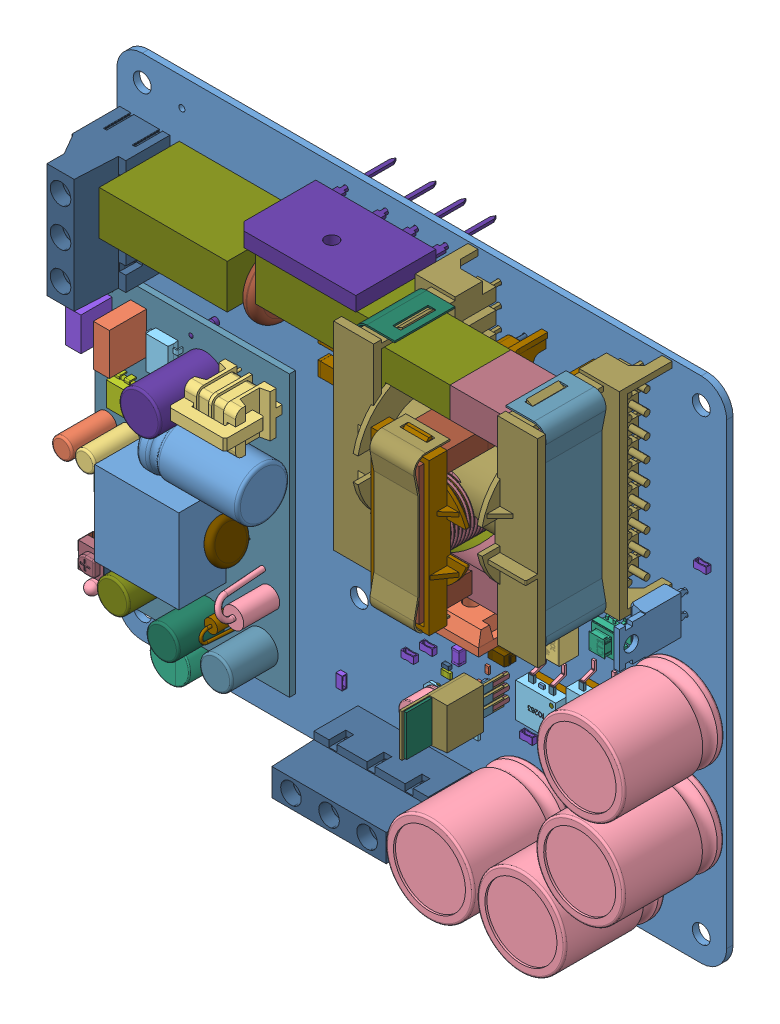
SolidWorks assembly VFD, configuration Default. Lengths in mm.
Overall size (152.4 127.13 60.49).
435 component instances, 101 part files, 0 mates.
Components (placement in the parent):
- Board-1: Board [Default] at origin size (152.4 127.13 1.59)
- R32-1: R32 [Default] at origin size (1.75 0.95 0.55)
  - RES_0603_(1608_metric)-1: RES_0603_(1608_metric) [Default] at (62.5869 45.7709 -0.013) size (1.75 0.95 0.55)
- C29-1: C29 [Default] at origin size (6.6 7 7.01)
  - User_Library-CAPSMD6_3x7-1: User_Library-CAPSMD6_3x7 [Default] at (80.5194 27.0821 0) x (1 0 0) z (0 0 1) size (6.6 7 7.01)
    - User_Library-CAPSMD6_3x3_9_CAP003-1: User_Library-CAPSMD6_3x3_9_CAP003 [Default] at origin size (0.65 2.6 0.32)
    - User_Library-CAPSMD6_3x3_9_CAP-1: User_Library-CAPSMD6_3x3_9_CAP [Default] at origin size (6.3 6.3 6.37)
    - User_Library-CAPSMD6_3x3_9_CAP001-1: User_Library-CAPSMD6_3x3_9_CAP001 [Default] at origin size (6.6 6.6 0.64)
    - User_Library-CAPSMD6_3x3_9_CAP002-1: User_Library-CAPSMD6_3x3_9_CAP002 [Default] at origin size (5.11 1.47 0.01)
    - User_Library-CAPSMD6_3x3_9_CAP004-1: User_Library-CAPSMD6_3x3_9_CAP004 [Default] at origin size (0.65 2.6 0.32)
- C28-1: C28 [Default] at origin size (6.6 7 7.01)
  - User_Library-CAPSMD6_3x7-1: User_Library-CAPSMD6_3x7 [Default] at (87.6314 26.9551 0) size (6.6 7 7.01)
    - User_Library-CAPSMD6_3x3_9_CAP003-1: User_Library-CAPSMD6_3x3_9_CAP003 [Default] at origin size (0.65 2.6 0.32)
    - User_Library-CAPSMD6_3x3_9_CAP-1: User_Library-CAPSMD6_3x3_9_CAP [Default] at origin size (6.3 6.3 6.37)
    - User_Library-CAPSMD6_3x3_9_CAP001-1: User_Library-CAPSMD6_3x3_9_CAP001 [Default] at origin size (6.6 6.6 0.64)
    - User_Library-CAPSMD6_3x3_9_CAP002-1: User_Library-CAPSMD6_3x3_9_CAP002 [Default] at origin size (5.11 1.47 0.01)
    - User_Library-CAPSMD6_3x3_9_CAP004-1: User_Library-CAPSMD6_3x3_9_CAP004 [Default] at origin size (0.65 2.6 0.32)
- TP17-1: TP17 [Default] at origin size (1.6 3.2 1.25)
  - c-1625854-1-ba-3d-1: c-1625854-1-ba-3d [Default] at (64.0474 73.9139 0.635) x (0 1 0) z (1 0 0) size (3.2 1.25 1.6)
- TP16-1: TP16 [Default] at origin size (3.2 1.6 1.25)
  - c-1625854-1-ba-3d-1: c-1625854-1-ba-3d [Default] at (73.7884 31.5341 0.635) x (-1 0 0) z (0 1 0) size (3.2 1.25 1.6)
- TP15-1: TP15 [Default] at origin size (3.2 1.6 1.25)
  - c-1625854-1-ba-3d-1: c-1625854-1-ba-3d [Default] at (103.5063 28.8671 0.635) x (-1 0 0) z (0 1 0) size (3.2 1.25 1.6)
- TP14-1: TP14 [Default] at origin size (3.2 1.6 1.25)
  - c-1625854-1-ba-3d-1: c-1625854-1-ba-3d [Default] at (97.9183 48.5521 0.635) x (-1 0 0) z (0 1 0) size (3.2 1.25 1.6)
- TP13-1: TP13 [Default] at origin size (1.6 3.2 1.25)
  - c-1625854-1-ba-3d-1: c-1625854-1-ba-3d [Default] at (67.7812 74.8031 0.635) x (0 -1 0) z (-1 0 0) size (3.2 1.25 1.6)
- TP12-1: TP12 [Default] at origin size (3.2 1.6 1.25)
  - c-1625854-1-ba-3d-1: c-1625854-1-ba-3d [Default] at (81.6116 71.7677 0.635) x (-1 0 0) z (0 1 0) size (3.2 1.25 1.6)
- TP11-1: TP11 [Default] at origin size (1.6 3.2 1.25)
  - c-1625854-1-ba-3d-1: c-1625854-1-ba-3d [Default] at (72.9374 79.3749 0.635) x (0 1 0) z (1 0 0) size (3.2 1.25 1.6)
- TP10-1: TP10 [Default] at origin size (3.2 1.6 1.25)
  - c-1625854-1-ba-3d-1: c-1625854-1-ba-3d [Default] at (72.5184 42.9641 0.635) x (-1 0 0) z (0 1 0) size (3.2 1.25 1.6)
- TP9-1: TP9 [Default] at origin size (1.6 3.2 1.25)
  - c-1625854-1-ba-3d-1: c-1625854-1-ba-3d [Default] at (57.5704 16.8909 0.635) x (0 1 0) z (1 0 0) size (3.2 1.25 1.6)
- TP8-1: TP8 [Default] at origin size (3.2 1.6 1.25)
  - c-1625854-1-ba-3d-1: c-1625854-1-ba-3d [Default] at (120.0417 71.0565 0.635) x (-1 0 0) z (0 1 0) size (3.2 1.25 1.6)
- TP7-1: TP7 [Default] at origin size (3.2 1.6 1.25)
  - c-1625854-1-ba-3d-1: c-1625854-1-ba-3d [Default] at (78.4873 35.5981 0.635) x (-1 0 0) z (0 1 0) size (3.2 1.25 1.6)
- TP6-1: TP6 [Default] at origin size (3.2 1.6 1.25)
  - c-1625854-1-ba-3d-1: c-1625854-1-ba-3d [Default] at (97.9183 53.7591 0.635) x (-1 0 0) z (0 1 0) size (3.2 1.25 1.6)
- TP5-1: TP5 [Default] at origin size (1.6 3.2 1.25)
  - c-1625854-1-ba-3d-1: c-1625854-1-ba-3d [Default] at (93.6774 68.9609 0.635) x (0 1 0) z (1 0 0) size (3.2 1.25 1.6)
- TP4-1: TP4 [Default] at origin size (3.2 1.6 1.25)
  - c-1625854-1-ba-3d-1: c-1625854-1-ba-3d [Default] at (146.9149 87.5411 0.635) x (-1 0 0) z (0 1 0) size (3.2 1.25 1.6)
- TP3-1: TP3 [Default] at origin size (3.2 1.6 1.25)
  - c-1625854-1-ba-3d-1: c-1625854-1-ba-3d [Default] at (135.5102 72.6059 0.635) x (1 0 0) z (0 -1 0) size (3.2 1.25 1.6)
- TP2-1: TP2 [Default] at origin size (1.6 3.2 1.25)
  - c-1625854-1-ba-3d-1: c-1625854-1-ba-3d [Default] at (80.9384 85.5979 0.635) x (0 1 0) z (1 0 0) size (3.2 1.25 1.6)
- D11-1: D11 [Default] at origin size (1.35 2.6 1.1)
  - SOD323-1: SOD323 [Default] at (65.7872 47.0101 0) x (0 -1 0) z (0 0 1) size (2.6 1.35 1.1)
- P2-1: P2 [Default] at origin size (29.16 12.5 26.5)
  - c-796739-3-b-3d-1: c-796739-3-b-3d [Default] at (74.682 0.5047 7) x (1 0 0) z (0 -1 0) size (29.16 26.5 12.5)
- P1-1: P1 [Default] at origin size (12.5 29.16 26.5)
  - c-796739-3-b-3d-1: c-796739-3-b-3d [Default] at (0.887 98.6742 7) x (0 -1 0) z (-1 0 0) size (29.16 26.5 12.5)
- VR1-1: VR1 [Default] at origin size (4.2 15.5 21.5)
  - User_Library-S14K25_MOV-1: User_Library-S14K25_MOV [Default] at (51.4159 105.2829 0.5) x (0 -1 0) z (-1 0 0) size (15.5 21.5 4.2)
- L2-1: L2 [Default] at origin size (51 49.6 42.6)
  - User_Library-ETD44_NO_AIRGAP-1: User_Library-ETD44_NO_AIRGAP [Default] at (113.2599 101.8636 0) x (0 1 0) z (0 0 1) size (49.6 51 42.6)
    - User_Library-ETD44_NO_AIRGAP_CoilFormerETD44-1: User_Library-ETD44_NO_AIRGAP_CoilFormerETD44 [Default] at origin size (49.6 51 42.6)
    - User_Library-ETD44_NO_AIRGAP_ETD44_core1-1: User_Library-ETD44_NO_AIRGAP_ETD44_core1 [Default] at origin size (43.8 22.5 15.2)
    - User_Library-ETD44_NO_AIRGAP_ClipETD44_2-1: User_Library-ETD44_NO_AIRGAP_ClipETD44_2 [Default] at origin size (48.8 10 15)
    - User_Library-ETD44_NO_AIRGAP_ClipETD44_1-1: User_Library-ETD44_NO_AIRGAP_ClipETD44_1 [Default] at origin size (48.8 10 15)
    - User_Library-ETD44_NO_AIRGAP_ETD44_core2-1: User_Library-ETD44_NO_AIRGAP_ETD44_core2 [Default] at origin size (43.8 22.5 15.2)
- D5-1: D5 [Default] at origin size (4.7 2.71 1.1)
  - 1281330688-1: 1281330688 [Default] at (102.8713 61.722 0) x (1 0 0) z (0 0 1) size (4.7 2.71 1.1)
    - Body-1: Body [Default] at (-2 -1.35 0) size (4.01 2.71 1.1)
      - Open_CASCADE_STEP_translator_6.8_1.1.1-1: Open_CASCADE_STEP_translator_6.8_1.1.1 [Default] at origin size (4.01 2.71 1.1)
    - lead-1: lead [Default] at (-2.35 -0.875 0) size (0.72 1.75 0.2)
    - lead-2: lead [Default] at (2.35 0.875 0) x (-1 0 0) z (0 0 1) size (0.72 1.75 0.2)
- D2-1: D2 [Default] at origin size (4.5 9.65 28.38)
  - User_Library-TO_220-2-1: User_Library-TO_220-2 [Default] at (144.3394 76.1879 4.445) x (0 -1 0) z (0 0 -1) size (9.65 4.5 28.38)
- Q1-1: Q1 [Default] at origin size (15.9 5.1 41.13)
  - User_Library-PG-TO247-3-21-1: User_Library-PG-TO247-3-21 [Default] at (115.7489 63.7671 4.3942) x (-1 0 0) z (0 1 0) size (15.9 41.13 5.1)
- U1-1: U1 [Default] at origin size (13.01 10.3 2.66)
  - 809572592-1: 809572592 [Default] at (83.9483 50.292 0) x (0 1 0) z (0 0 1) size (10.3 13.01 2.66)
    - Open_CASCADE_STEP_translator_6.8_1.1-1: Open_CASCADE_STEP_translator_6.8_1.1 [Default] at (-3.8 -6.5 0.001) size (0.95 0.95 0)
    - Body_2-1: Body_2 [Default] at (-3.8 -6.5 0) size (7.61 13.01 2.56)
      - Open_CASCADE_STEP_translator_6.8_1.2.1-1: Open_CASCADE_STEP_translator_6.8_1.2.1 [Default] at origin size (7.61 13.01 2.56)
    - Leader-1: Leader [Default] at (-3.8 -5.715 0) x (-1 0 0) z (0 0 1) size (1.35 0.41 1.43)
    - Leader-2: Leader [Default] at (-3.8 -4.445 0) x (-1 0 0) z (0 0 1) size (1.35 0.41 1.43)
    - Leader-3: Leader [Default] at (-3.8 -3.175 0) x (-1 0 0) z (0 0 1) size (1.35 0.41 1.43)
    - Leader-4: Leader [Default] at (-3.8 -1.905 0) x (-1 0 0) z (0 0 1) size (1.35 0.41 1.43)
    - Leader-5: Leader [Default] at (-3.8 -0.635 0) x (-1 0 0) z (0 0 1) size (1.35 0.41 1.43)
    - Leader-6: Leader [Default] at (-3.8 0.635 0) x (-1 0 0) z (0 0 1) size (1.35 0.41 1.43)
    - Leader-7: Leader [Default] at (-3.8 1.905 0) x (-1 0 0) z (0 0 1) size (1.35 0.41 1.43)
    - Leader-8: Leader [Default] at (-3.8 3.175 0) x (-1 0 0) z (0 0 1) size (1.35 0.41 1.43)
    - Leader-9: Leader [Default] at (-3.8 4.445 0) x (-1 0 0) z (0 0 1) size (1.35 0.41 1.43)
    - Leader-10: Leader [Default] at (-3.8 5.715 0) x (-1 0 0) z (0 0 1) size (1.35 0.41 1.43)
    - Leader-11: Leader [Default] at (3.8 -5.715 0) size (1.35 0.41 1.43)
    - Leader-12: Leader [Default] at (3.8 -4.445 0) size (1.35 0.41 1.43)
    - Leader-13: Leader [Default] at (3.8 -3.175 0) size (1.35 0.41 1.43)
    - Leader-14: Leader [Default] at (3.8 -1.905 0) size (1.35 0.41 1.43)
    - Leader-15: Leader [Default] at (3.8 -0.635 0) size (1.35 0.41 1.43)
    - Leader-16: Leader [Default] at (3.8 0.635 0) size (1.35 0.41 1.43)
    - Leader-17: Leader [Default] at (3.8 1.905 0) size (1.35 0.41 1.43)
    - Leader-18: Leader [Default] at (3.8 3.175 0) size (1.35 0.41 1.43)
    - Leader-19: Leader [Default] at (3.8 4.445 0) size (1.35 0.41 1.43)
    - Leader-20: Leader [Default] at (3.8 5.715 0) size (1.35 0.41 1.43)
- TR1-1: TR1 [Default] at origin size (7.6 8.13 5.36)
  - Coilcraft-CST1-1: Coilcraft-CST1 [Default] at (125.2232 61.0871 0.1) x (0 1 0) z (1 0 0) size (8.13 5.36 7.6)
- R20-1: R20 [Default] at origin size (0.95 1.75 0.55)
  - RES_0603_(1608_metric)-1: RES_0603_(1608_metric) [Default] at (79.1224 40.132 -0.013) x (0 -1 0) z (0 0 1) size (1.75 0.95 0.55)
- R16-1: R16 [Default] at origin size (1.75 0.95 0.55)
  - RES_0603_(1608_metric)-1: RES_0603_(1608_metric) [Default] at (71.6292 54.6099 -0.013) x (-1 0 0) z (0 0 1) size (1.75 0.95 0.55)
- R13-1: R13 [Default] at origin size (0.95 1.75 0.55)
  - RES_0603_(1608_metric)-1: RES_0603_(1608_metric) [Default] at (68.5814 91.059 -0.013) x (0 -1 0) z (0 0 1) size (1.75 0.95 0.55)
- R10-1: R10 [Default] at origin size (2.2 1.35 0.7)
  - RES_0805_(2012_metric)-1: RES_0805_(2012_metric) [Default] at (71.1214 103.1241 -0.013) x (1 0 0) z (0 0 1) size (2.2 1.35 0.7)
- R9-1: R9 [Default] at origin size (2.2 1.35 0.7)
  - RES_0805_(2012_metric)-1: RES_0805_(2012_metric) [Default] at (67.5494 97.9171 -0.013) x (1 0 0) z (0 0 1) size (2.2 1.35 0.7)
- R6-1: R6 [Default] at origin size (2.2 1.35 0.7)
  - RES_0805_(2012_metric)-1: RES_0805_(2012_metric) [Default] at (66.5494 103.1241 -0.013) x (1 0 0) z (0 0 1) size (2.2 1.35 0.7)
- R5-1: R5 [Default] at origin size (2.2 1.35 0.7)
  - RES_0805_(2012_metric)-1: RES_0805_(2012_metric) [Default] at (63.5014 97.9171 -0.013) x (1 0 0) z (0 0 1) size (2.2 1.35 0.7)
- R4-1: R4 [Default] at origin size (0.95 1.75 0.55)
  - RES_0603_(1608_metric)-1: RES_0603_(1608_metric) [Default] at (95.8862 58 -0.013) x (0 1 0) z (0 0 1) size (1.75 0.95 0.55)
- C17-1: C17 [Default] at origin size (1.8 3.4 1.8)
  - CAPC3216X180N_-_1206_(3216_metric)-1: CAPC3216X180N_-_1206_(3216_metric) [Default] at (78.9952 61.7221 0) x (0 1 0) z (0 0 1) size (3.4 1.8 1.8)
- C18-1: C18 [Default] at origin size (1.8 3.4 1.8)
  - CAPC3216X180N_-_1206_(3216_metric)-1: CAPC3216X180N_-_1206_(3216_metric) [Default] at (86.3614 37.3379 0) x (0 -1 0) z (0 0 1) size (3.4 1.8 1.8)
- C16-1: C16 [Default] at origin size (4.9 3.6 2.8)
  - CAP_1812-1: CAP_1812 [Default] at (66.5492 87.2489 -0.013) x (-1 0 0) z (0 0 1) size (4.9 3.6 2.8)
- C15-1: C15 [Default] at origin size (0.9 1.7 0.9)
  - CAP_0603-1: CAP_0603 [Default] at (85.8533 60.706 -0.013) x (0 -1 0) z (0 0 1) size (1.7 0.9 0.9)
- C13-1: C13 [Default] at origin size (4.9 3.6 2.8)
  - CAP_1812-1: CAP_1812 [Default] at (66.5492 94.7419 -0.013) x (-1 0 0) z (0 0 1) size (4.9 3.6 2.8)
- C10-1: C10 [Default] at origin size (0.9 1.7 0.9)
  - CAP_0603-1: CAP_0603 [Default] at (94.1083 58.039 -0.013) x (0 -1 0) z (0 0 1) size (1.7 0.9 0.9)
- C7-1: C7 [Default] at origin size (0.9 1.7 0.9)
  - CAP_0603-1: CAP_0603 [Default] at (80.7732 40.132 -0.013) x (0 1 0) z (0 0 1) size (1.7 0.9 0.9)
- C8-1: C8 [Default] at origin size (0.9 1.7 0.9)
  - CAP_0603-1: CAP_0603 [Default] at (99.0614 72.898 -0.013) x (0 -1 0) z (0 0 1) size (1.7 0.9 0.9)
- C9-1: C9 [Default] at origin size (0.9 1.7 0.9)
  - CAP_0603-1: CAP_0603 [Default] at (101.0934 72.898 -0.013) x (0 -1 0) z (0 0 1) size (1.7 0.9 0.9)
- C11-1: C11 [Default] at origin size (3.4 1.8 1.8)
  - CAPC3216X180N_-_1206_(3216_metric)-1: CAPC3216X180N_-_1206_(3216_metric) [Default] at (128.7792 69.7229 0) x (-1 0 0) z (0 0 1) size (3.4 1.8 1.8)
- C12-1: C12 [Default] at origin size (1.7 0.9 0.9)
  - CAP_0603-1: CAP_0603 [Default] at (75.0583 51.6891 -0.013) x (1 0 0) z (0 0 1) size (1.7 0.9 0.9)
- C14-1: C14 [Default] at origin size (1.7 0.9 0.9)
  - CAP_0603-1: CAP_0603 [Default] at (71.7563 49.9111 -0.013) x (1 0 0) z (0 0 1) size (1.7 0.9 0.9)
- C19-1: C19 [Default] at origin size (0.9 1.7 0.9)
  - CAP_0603-1: CAP_0603 [Default] at (73.9152 61.468 -0.013) x (0 1 0) z (0 0 1) size (1.7 0.9 0.9)
- C24-1: C24 [Default] at origin size (0.9 1.7 0.9)
  - CAP_0603-1: CAP_0603 [Default] at (84.2022 60.706 -0.013) x (0 1 0) z (0 0 1) size (1.7 0.9 0.9)
- C25-1: C25 [Default] at origin size (1.7 0.9 0.9)
  - CAP_0603-1: CAP_0603 [Default] at (82.9322 33.0199 -0.013) x (-1 0 0) z (0 0 1) size (1.7 0.9 0.9)
- D4-1: D4 [Default] at origin size (3.6 1.96 1.08)
  - 809534704-1: 809534704 [Default] at (117.5503 75.311 0) x (1 0 0) z (0 0 1) size (3.6 1.96 1.08)
    - Body_3-1: Body_3 [Default] at (-1.5 -0.975 0) size (3.01 1.96 1.08)
      - Open_CASCADE_STEP_translator_6.8_1.1.1_2-1: Open_CASCADE_STEP_translator_6.8_1.1.1_2 [Default] at origin size (3.01 1.96 1.08)
    - lead_2-1: lead_2 [Default] at (-1.8 -0.4125 0) size (0.68 0.82 0.2)
    - lead_2-2: lead_2 [Default] at (1.8 0.4125 0) x (-1 0 0) z (0 0 1) size (0.68 0.82 0.2)
- D8-1: D8 [Default] at origin size (10 15.67 4.89)
  - SW3dPS-TO263-3S-1: SW3dPS-TO263-3S [Default] at (122.0482 47.6011 1.6271) x (-1 0 0) z (0 0 1) size (10 15.67 4.89)
    - SW3dPS-TO263-3S_Board9-1: SW3dPS-TO263-3S_Board9 [Default] at (0 0 -0.0938) size (0.01 0.01 0.11)
    - SW3dPS-TO263-3S_Free-Models5-1: SW3dPS-TO263-3S_Free-Models5 [Default] at origin size (10 15.67 4.89)
      - SW3dPS-TO263-3S_450155985-1: SW3dPS-TO263-3S_450155985 [Default] at (2.54 -0.83 1.2127) size (1.2 1.68 0.6)
        - SW3dPS-TO263-3S_Extruded14-1: SW3dPS-TO263-3S_Extruded14 [Default] at origin size (1.2 1.68 0.6)
      - SW3dPS-TO263-3S_450154961-1: SW3dPS-TO263-3S_450154961 [Default] at (0.7 4.37 3.1727) size (0.72 1.1 0.19)
        - SW3dPS-TO263-3S_Extruded11-1: SW3dPS-TO263-3S_Extruded11 [Default] at origin size (0.72 1.1 0.19)
      - SW3dPS-TO263-3S_449923505-1: SW3dPS-TO263-3S_449923505 [Default] at (-3.9039 1.099 3.1727) size (1 1 0.01)
        - SW3dPS-TO263-3S_Cylinder1-1: SW3dPS-TO263-3S_Cylinder1 [Default] at origin size (1 1 0.01)
      - SW3dPS-TO263-3S_450155217-1: SW3dPS-TO263-3S_450155217 [Default] at (-1.115 4.37 3.1727) size (0.93 1.1 0.11)
        - SW3dPS-TO263-3S_Extruded12-1: SW3dPS-TO263-3S_Extruded12 [Default] at origin size (0.93 1.1 0.11)
      - SW3dPS-TO263-3S_450154833-1: SW3dPS-TO263-3S_450154833 [Default] at (1.555 4.37 3.1727) size (0.79 1.1 0.01)
        - SW3dPS-TO263-3S_Extruded21-1: SW3dPS-TO263-3S_Extruded21 [Default] at origin size (0.79 1.1 0.01)
      - SW3dPS-TO263-3S_450156369-1: SW3dPS-TO263-3S_450156369 [Default] at (0 -0.395 1.3127) size (1.2 0.81 0.5)
        - SW3dPS-TO263-3S_Extruded16-1: SW3dPS-TO263-3S_Extruded16 [Default] at origin size (1.2 0.81 0.5)
      - SW3dPS-TO263-3S_450155089-1: SW3dPS-TO263-3S_450155089 [Default] at (-0.165 4.37 3.1727) size (0.77 1.1 0.01)
        - SW3dPS-TO263-3S_Extruded19-1: SW3dPS-TO263-3S_Extruded19 [Default] at origin size (0.77 1.1 0.01)
      - SW3dPS-TO263-3S_450155985-2: SW3dPS-TO263-3S_450155985 [Default] at (-2.54 -0.83 1.2127) size (1.2 1.68 0.6)
        - SW3dPS-TO263-3S_Extruded14-1: SW3dPS-TO263-3S_Extruded14 [Default] at origin size (1.2 1.68 0.6)
      - SW3dPS-TO263-3S_PIN1-1: SW3dPS-TO263-3S_PIN1 [Default] at (-2.5273 -0.09 1.5627) x (0 1 0) z (-1 0 0) size (5 3.43 0.8)
        - SW3dPS-TO263-3S_Board5-1: SW3dPS-TO263-3S_Board5 [Default] at (0 0 -0.0938) size (0.01 0.01 0.11)
        - SW3dPS-TO263-3S_Free-Models6-1: SW3dPS-TO263-3S_Free-Models6 [Default] at origin size (5 3.43 0.8)
          - SW3dPS-TO263-3S_453496145-1: SW3dPS-TO263-3S_453496145 [Default] at (-2.4 1.465 -0.3873) size (5 3.43 0.8)
            - SW3dPS-TO263-3S_Extruded13-1: SW3dPS-TO263-3S_Extruded13 [Default] at origin size (5 3.43 0.8)
      - SW3dPS-TO263-3S_BODY3-1: SW3dPS-TO263-3S_BODY3 [Default] at (0 0.1 0.0127) size (10 10.68 4.78)
        - SW3dPS-TO263-3S_Free-Models7-1: SW3dPS-TO263-3S_Free-Models7 [Default] at origin size (10 10.68 4.78)
          - SW3dPS-TO263-3S_BODY4-1: SW3dPS-TO263-3S_BODY4 [Default] at (0.0127 0 1.5827) x (0 0 1) z (-1 0 0) size (3.15 9 10)
            - SW3dPS-TO263-3S_Free-Models8-1: SW3dPS-TO263-3S_Free-Models8 [Default] at origin size (3.15 9 10)
              - SW3dPS-TO263-3S_453496017-1: SW3dPS-TO263-3S_453496017 [Default] at (0 4.4 -4.9873) size (3.15 9 10)
                - SW3dPS-TO263-3S_Extruded18-1: SW3dPS-TO263-3S_Extruded18 [Default] at origin size (3.15 9 10)
            - SW3dPS-TO263-3S_Board7-1: SW3dPS-TO263-3S_Board7 [Default] at (0 0 -0.0938) size (0.01 0.01 0.11)
          - SW3dPS-TO263-3S_BODY5-1: SW3dPS-TO263-3S_BODY5 [Default] at (0 0 0.0127) size (10 10.68 1.65)
            - SW3dPS-TO263-3S_Board6-1: SW3dPS-TO263-3S_Board6 [Default] at (0 0 -0.0938) size (0.01 0.01 0.11)
            - SW3dPS-TO263-3S_Free-Models9-1: SW3dPS-TO263-3S_Free-Models9 [Default] at origin size (10 10.68 1.65)
              - SW3dPS-TO263-3S_453494353-1: SW3dPS-TO263-3S_453494353 [Default] at (0 7.15 -1.6373) size (10 6.86 1.65)
                - SW3dPS-TO263-3S_Extruded15-1: SW3dPS-TO263-3S_Extruded15 [Default] at origin size (10 6.86 1.65)
              - SW3dPS-TO263-3S_453494225-1: SW3dPS-TO263-3S_453494225 [Default] at (0 4.4 -1.6373) size (10 9 1.65)
                - SW3dPS-TO263-3S_Extruded17-1: SW3dPS-TO263-3S_Extruded17 [Default] at origin size (10 9 1.65)
        - SW3dPS-TO263-3S_Board8-1: SW3dPS-TO263-3S_Board8 [Default] at (0 0 -0.0938) size (0.01 0.01 0.11)
      - SW3dPS-TO263-3S_PIN1-2: SW3dPS-TO263-3S_PIN1 [Default] at (2.5527 -0.09 1.5627) x (0 1 0) z (-1 0 0) size (5 3.43 0.8)
        - SW3dPS-TO263-3S_Board5-1: SW3dPS-TO263-3S_Board5 [Default] at (0 0 -0.0938) size (0.01 0.01 0.11)
        - SW3dPS-TO263-3S_Free-Models6-1: SW3dPS-TO263-3S_Free-Models6 [Default] at origin size (5 3.43 0.8)
          - SW3dPS-TO263-3S_453496145-1: SW3dPS-TO263-3S_453496145 [Default] at (-2.4 1.465 -0.3873) size (5 3.43 0.8)
            - SW3dPS-TO263-3S_Extruded13-1: SW3dPS-TO263-3S_Extruded13 [Default] at origin size (5 3.43 0.8)
      - SW3dPS-TO263-3S_450155473-1: SW3dPS-TO263-3S_450155473 [Default] at (-1.945 4.37 3.1727) size (0.77 1.1 0.01)
        - SW3dPS-TO263-3S_Extruded20-1: SW3dPS-TO263-3S_Extruded20 [Default] at origin size (0.77 1.1 0.01)
- D9-1: D9 [Default] at origin size (10 15.67 4.89)
  - SW3dPS-TO263-3S-1: SW3dPS-TO263-3S [Default] at (109.4752 42.9021 1.6271) x (-1 0 0) z (0 0 1) size (10 15.67 4.89)
    - SW3dPS-TO263-3S_Board9-1: SW3dPS-TO263-3S_Board9 [Default] at (0 0 -0.0938) size (0.01 0.01 0.11)
    - SW3dPS-TO263-3S_Free-Models5-1: SW3dPS-TO263-3S_Free-Models5 [Default] at origin size (10 15.67 4.89)
      - SW3dPS-TO263-3S_450155985-1: SW3dPS-TO263-3S_450155985 [Default] at (2.54 -0.83 1.2127) size (1.2 1.68 0.6)
        - SW3dPS-TO263-3S_Extruded14-1: SW3dPS-TO263-3S_Extruded14 [Default] at origin size (1.2 1.68 0.6)
      - SW3dPS-TO263-3S_450154961-1: SW3dPS-TO263-3S_450154961 [Default] at (0.7 4.37 3.1727) size (0.72 1.1 0.19)
        - SW3dPS-TO263-3S_Extruded11-1: SW3dPS-TO263-3S_Extruded11 [Default] at origin size (0.72 1.1 0.19)
      - SW3dPS-TO263-3S_449923505-1: SW3dPS-TO263-3S_449923505 [Default] at (-3.9039 1.099 3.1727) size (1 1 0.01)
        - SW3dPS-TO263-3S_Cylinder1-1: SW3dPS-TO263-3S_Cylinder1 [Default] at origin size (1 1 0.01)
      - SW3dPS-TO263-3S_450155217-1: SW3dPS-TO263-3S_450155217 [Default] at (-1.115 4.37 3.1727) size (0.93 1.1 0.11)
        - SW3dPS-TO263-3S_Extruded12-1: SW3dPS-TO263-3S_Extruded12 [Default] at origin size (0.93 1.1 0.11)
      - SW3dPS-TO263-3S_450154833-1: SW3dPS-TO263-3S_450154833 [Default] at (1.555 4.37 3.1727) size (0.79 1.1 0.01)
        - SW3dPS-TO263-3S_Extruded21-1: SW3dPS-TO263-3S_Extruded21 [Default] at origin size (0.79 1.1 0.01)
      - SW3dPS-TO263-3S_450156369-1: SW3dPS-TO263-3S_450156369 [Default] at (0 -0.395 1.3127) size (1.2 0.81 0.5)
        - SW3dPS-TO263-3S_Extruded16-1: SW3dPS-TO263-3S_Extruded16 [Default] at origin size (1.2 0.81 0.5)
      - SW3dPS-TO263-3S_450155089-1: SW3dPS-TO263-3S_450155089 [Default] at (-0.165 4.37 3.1727) size (0.77 1.1 0.01)
        - SW3dPS-TO263-3S_Extruded19-1: SW3dPS-TO263-3S_Extruded19 [Default] at origin size (0.77 1.1 0.01)
      - SW3dPS-TO263-3S_450155985-2: SW3dPS-TO263-3S_450155985 [Default] at (-2.54 -0.83 1.2127) size (1.2 1.68 0.6)
        - SW3dPS-TO263-3S_Extruded14-1: SW3dPS-TO263-3S_Extruded14 [Default] at origin size (1.2 1.68 0.6)
      - SW3dPS-TO263-3S_PIN1-1: SW3dPS-TO263-3S_PIN1 [Default] at (-2.5273 -0.09 1.5627) x (0 1 0) z (-1 0 0) size (5 3.43 0.8)
        - SW3dPS-TO263-3S_Board5-1: SW3dPS-TO263-3S_Board5 [Default] at (0 0 -0.0938) size (0.01 0.01 0.11)
        - SW3dPS-TO263-3S_Free-Models6-1: SW3dPS-TO263-3S_Free-Models6 [Default] at origin size (5 3.43 0.8)
          - SW3dPS-TO263-3S_453496145-1: SW3dPS-TO263-3S_453496145 [Default] at (-2.4 1.465 -0.3873) size (5 3.43 0.8)
            - SW3dPS-TO263-3S_Extruded13-1: SW3dPS-TO263-3S_Extruded13 [Default] at origin size (5 3.43 0.8)
      - SW3dPS-TO263-3S_BODY3-1: SW3dPS-TO263-3S_BODY3 [Default] at (0 0.1 0.0127) size (10 10.68 4.78)
        - SW3dPS-TO263-3S_Free-Models7-1: SW3dPS-TO263-3S_Free-Models7 [Default] at origin size (10 10.68 4.78)
          - SW3dPS-TO263-3S_BODY4-1: SW3dPS-TO263-3S_BODY4 [Default] at (0.0127 0 1.5827) x (0 0 1) z (-1 0 0) size (3.15 9 10)
            - SW3dPS-TO263-3S_Free-Models8-1: SW3dPS-TO263-3S_Free-Models8 [Default] at origin size (3.15 9 10)
              - SW3dPS-TO263-3S_453496017-1: SW3dPS-TO263-3S_453496017 [Default] at (0 4.4 -4.9873) size (3.15 9 10)
                - SW3dPS-TO263-3S_Extruded18-1: SW3dPS-TO263-3S_Extruded18 [Default] at origin size (3.15 9 10)
            - SW3dPS-TO263-3S_Board7-1: SW3dPS-TO263-3S_Board7 [Default] at (0 0 -0.0938) size (0.01 0.01 0.11)
          - SW3dPS-TO263-3S_BODY5-1: SW3dPS-TO263-3S_BODY5 [Default] at (0 0 0.0127) size (10 10.68 1.65)
            - SW3dPS-TO263-3S_Board6-1: SW3dPS-TO263-3S_Board6 [Default] at (0 0 -0.0938) size (0.01 0.01 0.11)
            - SW3dPS-TO263-3S_Free-Models9-1: SW3dPS-TO263-3S_Free-Models9 [Default] at origin size (10 10.68 1.65)
              - SW3dPS-TO263-3S_453494353-1: SW3dPS-TO263-3S_453494353 [Default] at (0 7.15 -1.6373) size (10 6.86 1.65)
                - SW3dPS-TO263-3S_Extruded15-1: SW3dPS-TO263-3S_Extruded15 [Default] at origin size (10 6.86 1.65)
              - SW3dPS-TO263-3S_453494225-1: SW3dPS-TO263-3S_453494225 [Default] at (0 4.4 -1.6373) size (10 9 1.65)
                - SW3dPS-TO263-3S_Extruded17-1: SW3dPS-TO263-3S_Extruded17 [Default] at origin size (10 9 1.65)
        - SW3dPS-TO263-3S_Board8-1: SW3dPS-TO263-3S_Board8 [Default] at (0 0 -0.0938) size (0.01 0.01 0.11)
      - SW3dPS-TO263-3S_PIN1-2: SW3dPS-TO263-3S_PIN1 [Default] at (2.5527 -0.09 1.5627) x (0 1 0) z (-1 0 0) size (5 3.43 0.8)
        - SW3dPS-TO263-3S_Board5-1: SW3dPS-TO263-3S_Board5 [Default] at (0 0 -0.0938) size (0.01 0.01 0.11)
        - SW3dPS-TO263-3S_Free-Models6-1: SW3dPS-TO263-3S_Free-Models6 [Default] at origin size (5 3.43 0.8)
          - SW3dPS-TO263-3S_453496145-1: SW3dPS-TO263-3S_453496145 [Default] at (-2.4 1.465 -0.3873) size (5 3.43 0.8)
            - SW3dPS-TO263-3S_Extruded13-1: SW3dPS-TO263-3S_Extruded13 [Default] at origin size (5 3.43 0.8)
      - SW3dPS-TO263-3S_450155473-1: SW3dPS-TO263-3S_450155473 [Default] at (-1.945 4.37 3.1727) size (0.77 1.1 0.01)
        - SW3dPS-TO263-3S_Extruded20-1: SW3dPS-TO263-3S_Extruded20 [Default] at origin size (0.77 1.1 0.01)
- Q2-1: Q2 [Default] at origin size (4.86 10.67 30.99)
  - 42ctq030-1: 42ctq030 [Default] at (98.0452 35.6871 7.62) x (0 1 0) z (1 0 0) size (10.67 30.99 4.83)
  - 809727544-1: 809727544 [Default] at (97.5373 33.147 -3.048) size (1.02 1.02 7.11)
    - Extruded-1: Extruded [Default] at origin size (1.02 1.02 7.11)
  - 809727680-1: 809727680 [Default] at (97.5373 33.147 4.064) size (1.02 1.78 4.06)
    - Extruded_2-1: Extruded_2 [Default] at origin size (1.02 1.78 4.06)
  - 809727544-2: 809727544 [Default] at (97.5373 35.687 -3.048) size (1.02 1.02 7.11)
    - Extruded-1: Extruded [Default] at origin size (1.02 1.02 7.11)
  - 809727680-2: 809727680 [Default] at (97.5373 35.687 4.064) size (1.02 1.78 4.06)
    - Extruded_2-1: Extruded_2 [Default] at origin size (1.02 1.78 4.06)
  - 809727680-3: 809727680 [Default] at (97.5373 38.227 4.064) size (1.02 1.78 4.06)
    - Extruded_2-1: Extruded_2 [Default] at origin size (1.02 1.78 4.06)
  - 809727544-3: 809727544 [Default] at (97.5373 38.227 -3.048) size (1.02 1.02 7.11)
    - Extruded-1: Extruded [Default] at origin size (1.02 1.02 7.11)
  - 809727816-1: 809727816 [Default] at (95.1243 35.687 8.128) size (1.27 10.16 15.24)
    - Extruded_3-1: Extruded_3 [Default] at origin size (1.27 10.16 15.24)
- R1-1: R1 [Default] at origin size (1.75 0.95 0.55)
  - RES_0603_(1608_metric)-1: RES_0603_(1608_metric) [Default] at (100.0773 75.3111 -0.013) size (1.75 0.95 0.55)
- R2-1: R2 [Default] at origin size (1.35 2.2 0.7)
  - RES_0805_(2012_metric)-1: RES_0805_(2012_metric) [Default] at (112.1304 74.3959 -0.013) x (0 -1 0) z (0 0 1) size (2.2 1.35 0.7)
- R3-1: R3 [Default] at origin size (1.35 2.2 0.7)
  - RES_0805_(2012_metric)-1: RES_0805_(2012_metric) [Default] at (114.1624 74.4119 -0.013) x (0 -1 0) z (0 0 1) size (2.2 1.35 0.7)
- R12-1: R12 [Default] at origin size (0.95 1.75 0.55)
  - RES_0603_(1608_metric)-1: RES_0603_(1608_metric) [Default] at (104.3954 71.12 -0.013) x (0 -1 0) z (0 0 1) size (1.75 0.95 0.55)
- R7-1: R7 [Default] at origin size (2.2 1.35 0.7)
  - RES_0805_(2012_metric)-1: RES_0805_(2012_metric) [Default] at (117.4761 25.7809 -0.013) x (-1 0 0) z (0 0 1) size (2.2 1.35 0.7)
- R8-1: R8 [Default] at origin size (1.75 0.95 0.55)
  - RES_0603_(1608_metric)-1: RES_0603_(1608_metric) [Default] at (75.0582 49.9109 -0.013) x (-1 0 0) z (0 0 1) size (1.75 0.95 0.55)
- R11-1: R11 [Default] at origin size (1.75 0.95 0.55)
  - RES_0603_(1608_metric)-1: RES_0603_(1608_metric) [Default] at (71.7563 51.6891 -0.013) x (1 0 0) z (0 0 1) size (1.75 0.95 0.55)
- R14-1: R14 [Default] at origin size (2.2 1.35 0.7)
  - RES_0805_(2012_metric)-1: RES_0805_(2012_metric) [Default] at (117.6031 23.6219 -0.013) x (-1 0 0) z (0 0 1) size (2.2 1.35 0.7)
- R17-1: R17 [Default] at origin size (2.2 1.35 0.7)
  - RES_0805_(2012_metric)-1: RES_0805_(2012_metric) [Default] at (114.0312 25.7809 -0.013) x (-1 0 0) z (0 0 1) size (2.2 1.35 0.7)
- R19-1: R19 [Default] at origin size (2.2 1.35 0.7)
  - RES_0805_(2012_metric)-1: RES_0805_(2012_metric) [Default] at (114.0471 23.6219 -0.013) x (-1 0 0) z (0 0 1) size (2.2 1.35 0.7)
- R18-1: R18 [Default] at origin size (0.95 1.75 0.55)
  - RES_0603_(1608_metric)-1: RES_0603_(1608_metric) [Default] at (76.9634 61.468 -0.013) x (0 -1 0) z (0 0 1) size (1.75 0.95 0.55)
- R21-1: R21 [Default] at origin size (0.95 1.75 0.55)
  - RES_0603_(1608_metric)-1: RES_0603_(1608_metric) [Default] at (75.4392 61.468 -0.013) x (0 1 0) z (0 0 1) size (1.75 0.95 0.55)
- R24-1: R24 [Default] at origin size (0.95 1.75 0.55)
  - RES_0603_(1608_metric)-1: RES_0603_(1608_metric) [Default] at (82.6782 60.706 -0.013) x (0 1 0) z (0 0 1) size (1.75 0.95 0.55)
- R25-1: R25 [Default] at origin size (2.2 1.35 0.7)
  - RES_0805_(2012_metric)-1: RES_0805_(2012_metric) [Default] at (82.8051 31.2419 -0.013) x (-1 0 0) z (0 0 1) size (2.2 1.35 0.7)
- R26-1: R26 [Default] at origin size (0.95 1.75 0.55)
  - RES_0603_(1608_metric)-1: RES_0603_(1608_metric) [Default] at (81.0272 62.1538 -0.013) x (0 1 0) z (0 0 1) size (1.75 0.95 0.55)
- C1-1: C1 [Default] at origin size (32 11 20)
  - 809728768-1: 809728768 [Default] at (70.6473 112.522 0) size (32 11 20)
    - Extruded_4-1: Extruded_4 [Default] at origin size (32 11 20)
- C6-1: C6 [Default] at origin size (32 11 20)
  - 809728768-1: 809728768 [Default] at (31.5903 107.188 0) size (32 11 20)
    - Extruded_4-1: Extruded_4 [Default] at origin size (32 11 20)
- D1-1: D1 [Default] at origin size (30 4.9 37.5)
  - GBJ_4-SIP-1: GBJ_4-SIP [Default] at (69.7091 126.3419 5) x (1 0 0) z (0 0 -1) size (30 4.9 37.5)
- D3-1: D3 [Default] at origin size (5.21 2.6 2.43)
  - SW3dPS-DO-214AC_SMA-1: SW3dPS-DO-214AC_SMA [Default] at (97.2152 43.0529 1.4152) x (0 1 0) z (0 0 1) size (2.6 5.21 2.43)
- D6-1: D6 [Default] at origin size (5.21 2.6 2.43)
  - SW3dPS-DO-214AC_SMA-1: SW3dPS-DO-214AC_SMA [Default] at (95.5054 61.8491 1.4152) x (0 -1 0) z (0 0 1) size (2.6 5.21 2.43)
- D7-1: D7 [Default] at origin size (3.6 1.96 1.08)
  - 809534704-1: 809534704 [Default] at (107.5703 70.231 0) x (1 0 0) z (0 0 1) size (3.6 1.96 1.08)
    - Body_3-1: Body_3 [Default] at (-1.5 -0.975 0) size (3.01 1.96 1.08)
      - Open_CASCADE_STEP_translator_6.8_1.1.1_2-1: Open_CASCADE_STEP_translator_6.8_1.1.1_2 [Default] at origin size (3.01 1.96 1.08)
    - lead_2-1: lead_2 [Default] at (-1.8 -0.4125 0) size (0.68 0.82 0.2)
    - lead_2-2: lead_2 [Default] at (1.8 0.4125 0) x (-1 0 0) z (0 0 1) size (0.68 0.82 0.2)
- D10-1: D10 [Default] at origin size (1.96 3.6 1.08)
  - 809573488-1: 809573488 [Default] at (92.9653 33.147 0) x (0 -1 0) z (0 0 1) size (3.6 1.96 1.08)
    - Body_4-1: Body_4 [Default] at (-1.5 -0.975 0) size (3.01 1.96 1.08)
      - Open_CASCADE_STEP_translator_6.8_1.1.1_3-1: Open_CASCADE_STEP_translator_6.8_1.1.1_3 [Default] at origin size (3.01 1.96 1.08)
    - lead_3-1: lead_3 [Default] at (-1.8 -0.4125 0) size (0.68 0.82 0.2)
    - lead_3-2: lead_3 [Default] at (1.8 0.4125 0) x (-1 0 0) z (0 0 1) size (0.68 0.82 0.2)
- L3-1: L3 [Default] at origin size (7 9.6 4.96)
  - Coilcraft-SLR1050x-1: Coilcraft-SLR1050x [Default] at (111.8883 56.0069 0) x (0 -1 0) z (-1 0 0) size (9.6 4.96 7)
- R15-1: R15 [Default] at origin size (1.75 0.95 0.55)
  - RES_0603_(1608_metric)-1: RES_0603_(1608_metric) [Default] at (107.4433 72.1361 -0.013) x (1 0 0) z (0 0 1) size (1.75 0.95 0.55)
- R22-1: R22 [Default] at origin size (0.95 1.75 0.55)
  - RES_0603_(1608_metric)-1: RES_0603_(1608_metric) [Default] at (92.9654 37.211 -0.013) x (0 -1 0) z (0 0 1) size (1.75 0.95 0.55)
- R23-1: R23 [Default] at origin size (0.95 1.75 0.55)
  - RES_0603_(1608_metric)-1: RES_0603_(1608_metric) [Default] at (90.9334 32.893 -0.013) x (0 -1 0) z (0 0 1) size (1.75 0.95 0.55)
- C2-1: C2 [Default] at origin size (22 22 31.01)
  - Capacitor22x25-1: Capacitor22x25 [Default] at (131.7171 46.9078 -3.686) x (1 0 0) z (0 -1 0) size (22 31.01 22)
    - User_Library-ECEC2DP271BJ-1: User_Library-ECEC2DP271BJ [Default] at (8.9531 3.6858 17.317) size (22 25.01 22)
    - User_Library-CAP_EL_SNAP-IN_10_35x45_Valor_predeterminado-1: User_Library-CAP_EL_SNAP-IN_10_35x45_Valor_predeterminado [Default] at (14.4607 11.8368 29.4898) x (0.642788 0 0.766044) z (-0.766044 0 0.642788) size (3.5 7.01 5.68)
    - User_Library-CAP_EL_SNAP-IN_10_35x45_Valor_predeterminado-2: User_Library-CAP_EL_SNAP-IN_10_35x45_Valor_predeterminado [Default] at (2.8917 11.8368 4.8301) x (-0.67559 0 -0.737277) z (0.737277 0 -0.67559) size (3.5 7.01 5.68)
- C3-1: C3 [Default] at origin size (22 22 31.01)
  - Capacitor22x25-1: Capacitor22x25 [Default] at (131.8111 69.5138 -3.686) x (1 0 0) z (0 -1 0) size (22 31.01 22)
    - User_Library-ECEC2DP271BJ-1: User_Library-ECEC2DP271BJ [Default] at (8.9531 3.6858 17.317) size (22 25.01 22)
    - User_Library-CAP_EL_SNAP-IN_10_35x45_Valor_predeterminado-1: User_Library-CAP_EL_SNAP-IN_10_35x45_Valor_predeterminado [Default] at (14.4607 11.8368 29.4898) x (0.642788 0 0.766044) z (-0.766044 0 0.642788) size (3.5 7.01 5.68)
    - User_Library-CAP_EL_SNAP-IN_10_35x45_Valor_predeterminado-2: User_Library-CAP_EL_SNAP-IN_10_35x45_Valor_predeterminado [Default] at (2.8917 11.8368 4.8301) x (-0.67559 0 -0.737277) z (0.737277 0 -0.67559) size (3.5 7.01 5.68)
- C4-1: C4 [Default] at origin size (22 22 31.01)
  - Capacitor22x25-1: Capacitor22x25 [Default] at (120.4421 20.3032 -3.686) x (0 -1 0) z (-1 0 0) size (22 31.01 22)
    - User_Library-ECEC2DP271BJ-1: User_Library-ECEC2DP271BJ [Default] at (8.9531 3.6858 17.317) size (22 25.01 22)
    - User_Library-CAP_EL_SNAP-IN_10_35x45_Valor_predeterminado-1: User_Library-CAP_EL_SNAP-IN_10_35x45_Valor_predeterminado [Default] at (14.4607 11.8368 29.4898) x (0.642788 0 0.766044) z (-0.766044 0 0.642788) size (3.5 7.01 5.68)
    - User_Library-CAP_EL_SNAP-IN_10_35x45_Valor_predeterminado-2: User_Library-CAP_EL_SNAP-IN_10_35x45_Valor_predeterminado [Default] at (2.8917 11.8368 4.8301) x (-0.67559 0 -0.737277) z (0.737277 0 -0.67559) size (3.5 7.01 5.68)
- C5-1: C5 [Default] at origin size (22 22 31.01)
  - Capacitor22x25-1: Capacitor22x25 [Default] at (143.3021 20.3362 -3.686) x (0 -1 0) z (-1 0 0) size (22 31.01 22)
    - User_Library-ECEC2DP271BJ-1: User_Library-ECEC2DP271BJ [Default] at (8.9531 3.6858 17.317) size (22 25.01 22)
    - User_Library-CAP_EL_SNAP-IN_10_35x45_Valor_predeterminado-1: User_Library-CAP_EL_SNAP-IN_10_35x45_Valor_predeterminado [Default] at (14.4607 11.8368 29.4898) x (0.642788 0 0.766044) z (-0.766044 0 0.642788) size (3.5 7.01 5.68)
    - User_Library-CAP_EL_SNAP-IN_10_35x45_Valor_predeterminado-2: User_Library-CAP_EL_SNAP-IN_10_35x45_Valor_predeterminado [Default] at (2.8917 11.8368 4.8301) x (-0.67559 0 -0.737277) z (0.737277 0 -0.67559) size (3.5 7.01 5.68)
- C20-1: C20 [Default] at origin size (11.8 10.5 8)
  - User_Library-cap_10x10x8-1: User_Library-cap_10x10x8 [Default] at (20.9564 6.604 0) x (0 -1 0) z (-1 0 0) size (10.5 8 11.8)
- C21-1: C21 [Default] at origin size (3.6 2.8 2.2)
  - CAP_1210-1: CAP_1210 [Default] at (86.8692 38.4811 -1.5783) x (-1 0 0) z (0 0 -1) size (3.6 2.8 2.2)
- C22-1: C22 [Default] at origin size (2.2 1.45 1.35)
  - CAP_0805-1: CAP_0805 [Default] at (87.5042 41.0211 -1.5783) x (-1 0 0) z (0 0 -1) size (2.2 1.45 1.35)
- C23-1: C23 [Default] at origin size (2.2 1.45 1.35)
  - CAP_0805-1: CAP_0805 [Default] at (87.5042 42.9261 -1.5783) x (-1 0 0) z (0 0 -1) size (2.2 1.45 1.35)
- C26-1: C26 [Default] at origin size (4.9 3.6 2.8)
  - CAP_1812-1: CAP_1812 [Default] at (55.5002 90.9319 -0.013) x (-1 0 0) z (0 0 1) size (4.9 3.6 2.8)
- C27-1: C27 [Default] at origin size (4.9 3.6 2.8)
  - CAP_1812-1: CAP_1812 [Default] at (55.5002 83.6929 -0.013) x (-1 0 0) z (0 0 1) size (4.9 3.6 2.8)
- L1-1: L1 [Default] at origin size (26.36 39.3 49.7)
  - ETD_34_Vertical-1: ETD_34_Vertical [Default] at (126.0623 118.0749 0) x (0 1 0) z (1 0 0) size (39.3 49.7 26.36)
    - User_Library-ETD34-17-11_Vertical_Bobbin_Part_No._FD9640-1: User_Library-ETD34-17-11_Vertical_Bobbin_Part_No._FD9640 [Default] at (-19.65 26.6 -12.65) x (-1 0 0) z (0 0 1) size (39.3 49.7 26.36)
      - User_Library-ETD34-17-11_Vertical_Bobbin_Part_No._FD9640_FD9640-1: User_Library-ETD34-17-11_Vertical_Bobbin_Part_No._FD9640_FD9640 [Default] at origin size (39.3 42.6 26.36)
      - User_Library-ETD34-17-11_Vertical_Bobbin_Part_No._FD9640_1MM_RND_PIN-1: User_Library-ETD34-17-11_Vertical_Bobbin_Part_No._FD9640_1MM_RND_PIN [Default] at origin size (1 13.75 1.63)
      - User_Library-ETD34-17-11_Vertical_Bobbin_Part_No._FD9640_1MM_RND_PIN-2: User_Library-ETD34-17-11_Vertical_Bobbin_Part_No._FD9640_1MM_RND_PIN [Default] at (5.08 0 0) size (1 13.75 1.63)
      - User_Library-ETD34-17-11_Vertical_Bobbin_Part_No._FD9640_1MM_RND_PIN-3: User_Library-ETD34-17-11_Vertical_Bobbin_Part_No._FD9640_1MM_RND_PIN [Default] at (10.16 0 0) size (1 13.75 1.63)
      - User_Library-ETD34-17-11_Vertical_Bobbin_Part_No._FD9640_1MM_RND_PIN-4: User_Library-ETD34-17-11_Vertical_Bobbin_Part_No._FD9640_1MM_RND_PIN [Default] at (15.24 0 0) size (1 13.75 1.63)
      - User_Library-ETD34-17-11_Vertical_Bobbin_Part_No._FD9640_1MM_RND_PIN-5: User_Library-ETD34-17-11_Vertical_Bobbin_Part_No._FD9640_1MM_RND_PIN [Default] at (20.32 0 0) size (1 13.75 1.63)
      - User_Library-ETD34-17-11_Vertical_Bobbin_Part_No._FD9640_1MM_RND_PIN-6: User_Library-ETD34-17-11_Vertical_Bobbin_Part_No._FD9640_1MM_RND_PIN [Default] at (25.4 0 0) size (1 13.75 1.63)
      - User_Library-ETD34-17-11_Vertical_Bobbin_Part_No._FD9640_1MM_RND_PIN-7: User_Library-ETD34-17-11_Vertical_Bobbin_Part_No._FD9640_1MM_RND_PIN [Default] at (30.48 0 0) size (1 13.75 1.63)
      - User_Library-ETD34-17-11_Vertical_Bobbin_Part_No._FD9640_1MM_RND_PIN-8: User_Library-ETD34-17-11_Vertical_Bobbin_Part_No._FD9640_1MM_RND_PIN [Default] x (-1 0 0) z (0 0 -1) size (1 13.75 1.63)
      - User_Library-ETD34-17-11_Vertical_Bobbin_Part_No._FD9640_1MM_RND_PIN-9: User_Library-ETD34-17-11_Vertical_Bobbin_Part_No._FD9640_1MM_RND_PIN [Default] at (-5.08 0 0) x (-1 0 0) z (0 0 -1) size (1 13.75 1.63)
      - User_Library-ETD34-17-11_Vertical_Bobbin_Part_No._FD9640_1MM_RND_PIN-10: User_Library-ETD34-17-11_Vertical_Bobbin_Part_No._FD9640_1MM_RND_PIN [Default] at (-10.16 0 0) x (-1 0 0) z (0 0 -1) size (1 13.75 1.63)
      - User_Library-ETD34-17-11_Vertical_Bobbin_Part_No._FD9640_1MM_RND_PIN-11: User_Library-ETD34-17-11_Vertical_Bobbin_Part_No._FD9640_1MM_RND_PIN [Default] at (-15.24 0 0) x (-1 0 0) z (0 0 -1) size (1 13.75 1.63)
      - User_Library-ETD34-17-11_Vertical_Bobbin_Part_No._FD9640_1MM_RND_PIN-12: User_Library-ETD34-17-11_Vertical_Bobbin_Part_No._FD9640_1MM_RND_PIN [Default] at (-20.32 0 0) x (-1 0 0) z (0 0 -1) size (1 13.75 1.63)
      - User_Library-ETD34-17-11_Vertical_Bobbin_Part_No._FD9640_1MM_RND_PIN-13: User_Library-ETD34-17-11_Vertical_Bobbin_Part_No._FD9640_1MM_RND_PIN [Default] at (-25.4 0 0) x (-1 0 0) z (0 0 -1) size (1 13.75 1.63)
      - User_Library-ETD34-17-11_Vertical_Bobbin_Part_No._FD9640_1MM_RND_PIN-14: User_Library-ETD34-17-11_Vertical_Bobbin_Part_No._FD9640_1MM_RND_PIN [Default] at (-30.48 0 0) x (-1 0 0) z (0 0 -1) size (1 13.75 1.63)
      - User_Library-ETD34-17-11_Vertical_Bobbin_Part_No._FD9640_ETD34_CORE-1: User_Library-ETD34-17-11_Vertical_Bobbin_Part_No._FD9640_ETD34_CORE [Default] at (0 -16.7 0) size (34.2 17.3 10.8)
      - User_Library-ETD34-17-11_Vertical_Bobbin_Part_No._FD9640_ETD34_CORE-2: User_Library-ETD34-17-11_Vertical_Bobbin_Part_No._FD9640_ETD34_CORE [Default] at (0 17.9 0) x (-1 0 0) z (0 0 1) size (34.2 17.3 10.8)
      - User_Library-ETD34-17-11_Vertical_Bobbin_Part_No._FD9640_ETD34_CORE_CLIP-1: User_Library-ETD34-17-11_Vertical_Bobbin_Part_No._FD9640_ETD34_CORE_CLIP [Default] at (0 10.3 -5.5) x (0 -1 0) z (-1 0 0) size (9 11 38.6)
      - User_Library-ETD34-17-11_Vertical_Bobbin_Part_No._FD9640_ETD34_CORE_CLIP-2: User_Library-ETD34-17-11_Vertical_Bobbin_Part_No._FD9640_ETD34_CORE_CLIP [Default] at (0 -9.1 5.5) x (0 1 0) z (-1 0 0) size (9 11 38.6)
      - User_Library-ETD34-17-11_Vertical_Bobbin_Part_No._FD9640_ETD34_WINDING-1: User_Library-ETD34-17-11_Vertical_Bobbin_Part_No._FD9640_ETD34_WINDING [Default] at (0.2458 10.0424 -0.0108) x (-0.015539 -0.999863 0.005636) z (0.990175 -0.016171 -0.138898) size (20.6 14.6 14.6)
- MOD1-1: MOD1 [Default] at origin size (48.6 70 26)
  - vof-15-15-1: vof-15-15 [Default] at (28.4127 45.7124 2.5) x (0 1 0) z (1 0 0) size (70 1.5 48.6)
  - vof-15-15_2-1: vof-15-15_2 [Default] at (28.4127 45.7124 2.5) x (0 1 0) z (1 0 0) size (1.8 9.7 1.8)
  - vof-15-15_3-1: vof-15-15_3 [Default] at (28.4127 45.7124 2.5) x (0 1 0) z (1 0 0) size (1.8 9.7 1.8)
  - vof-15-15_4-1: vof-15-15_4 [Default] at (28.4127 45.7124 2.5) x (0 1 0) z (1 0 0) size (1.8 9.7 1.8)
  - vof-15-15_5-1: vof-15-15_5 [Default] at (28.4127 45.7124 2.5) x (0 1 0) z (1 0 0) size (1.8 9.7 1.8)
  - vof-15-15_6-1: vof-15-15_6 [Default] at (28.4127 45.7124 2.5) x (0 1 0) z (1 0 0) size (21 11.8 21)
  - vof-15-15_7-1: vof-15-15_7 [Default] at (28.4127 45.7124 2.5) x (0 1 0) z (1 0 0) size (10.4 9.3 4)
  - vof-15-15_8-1: vof-15-15_8 [Default] at (28.4127 45.7124 2.5) x (0 1 0) z (1 0 0) size (10.65 15 14.2)
  - vof-15-15_9-1: vof-15-15_9 [Default] at (28.4127 45.7124 2.5) x (0 1 0) z (1 0 0) size (3.5 5.5 3.5)
  - vof-15-15_10-1: vof-15-15_10 [Default] at (28.4127 45.7124 2.5) x (0 1 0) z (1 0 0) size (8.15 2.5 8)
  - vof-15-15_11-1: vof-15-15_11 [Default] at (28.4127 45.7124 2.5) x (0 1 0) z (1 0 0) size (8 3.35 4.6)
  - vof-15-15_12-1: vof-15-15_12 [Default] at (28.4127 45.7124 2.5) x (0 1 0) z (1 0 0) size (8 3.35 9.5)
  - vof-15-15_13-1: vof-15-15_13 [Default] at (28.4127 45.7124 2.5) x (0 1 0) z (1 0 0) size (8.4 7.8 3.8)
  - vof-15-15_14-1: vof-15-15_14 [Default] at (28.4127 45.7124 2.5) x (0 1 0) z (1 0 0) size (5.5 9.17 3.3)
  - vof-15-15_15-1: vof-15-15_15 [Default] at (28.4127 45.7124 2.5) x (0 1 0) z (1 0 0) size (2.5 5 0.4)
  - vof-15-15_16-1: vof-15-15_16 [Default] at (28.4127 45.7124 2.5) x (0 1 0) z (1 0 0) size (2.4 5 0.4)
  - vof-15-15_17-1: vof-15-15_17 [Default] at (28.4127 45.7124 2.5) x (0 1 0) z (1 0 0) size (2.4 5 0.4)
  - vof-15-15_18-1: vof-15-15_18 [Default] at (28.4127 45.7124 2.5) x (0 1 0) z (1 0 0) size (6.3 3.8 6.3)
  - vof-15-15_19-1: vof-15-15_19 [Default] at (28.4127 45.7124 2.5) x (0 1 0) z (1 0 0) size (8.1 11.6 8.1)
  - vof-15-15_20-1: vof-15-15_20 [Default] at (28.4127 45.7124 2.5) x (0 1 0) z (1 0 0) size (8.1 11.6 8.1)
  - vof-15-15_21-1: vof-15-15_21 [Default] at (28.4127 45.7124 2.5) x (0 1 0) z (1 0 0) size (8.1 11.6 8.1)
  - vof-15-15_22-1: vof-15-15_22 [Default] at (28.4127 45.7124 2.5) x (0 1 0) z (1 0 0) size (10.25 16.5 10.25)
  - vof-15-15_23-1: vof-15-15_23 [Default] at (28.4127 45.7124 2.5) x (0 1 0) z (1 0 0) size (10.16 11.26 4.68)
  - vof-15-15_24-1: vof-15-15_24 [Default] at (28.4127 45.7124 2.5) x (0 1 0) z (1 0 0) size (13 13 27.05)
  - vof-15-15_25-1: vof-15-15_25 [Default] at (28.4127 45.7124 2.5) x (0 1 0) z (1 0 0) size (5.15 11.25 5.15)
  - vof-15-15_26-1: vof-15-15_26 [Default] at (28.4127 45.7124 2.5) x (0 1 0) z (1 0 0) size (5.15 11.25 5.15)
  - vof-15-15_27-1: vof-15-15_27 [Default] at (28.4127 45.7124 2.5) x (0 1 0) z (1 0 0) size (8.58 12.85 5.15)
- R27-1: R27 [Default] at origin size (1.35 2.2 0.7)
  - RES_0805_(2012_metric)-1: RES_0805_(2012_metric) [Default] at (57.5323 94.6149 -0.013) x (0 -1 0) z (0 0 1) size (2.2 1.35 0.7)
- R28-1: R28 [Default] at origin size (1.35 2.2 0.7)
  - RES_0805_(2012_metric)-1: RES_0805_(2012_metric) [Default] at (57.5323 87.3759 -0.013) x (0 -1 0) z (0 0 1) size (2.2 1.35 0.7)
- R29-1: R29 [Default] at origin size (0.95 1.75 0.55)
  - RES_0603_(1608_metric)-1: RES_0603_(1608_metric) [Default] at (61.7234 69.342 -0.013) x (0 -1 0) z (0 0 1) size (1.75 0.95 0.55)
- R30-1: R30 [Default] at origin size (1.75 0.95 0.55)
  - RES_0603_(1608_metric)-1: RES_0603_(1608_metric) [Default] at (58.4603 80.7721 -0.013) x (1 0 0) z (0 0 1) size (1.75 0.95 0.55)
- R31-1: R31 [Default] at origin size (1.75 0.95 0.55)
  - RES_0603_(1608_metric)-1: RES_0603_(1608_metric) [Default] at (64.8983 49.9111 -0.013) x (1 0 0) z (0 0 1) size (1.75 0.95 0.55)
- TR2-1: TR2 [Default] at origin size (4.85 4.32 4.72)
  - 809727952-1: 809727952 [Default] at (59.7675 59.8297 4.699) size (0.15 1.14 0.03)
    - Extruded_5-1: Extruded_5 [Default] at origin size (0.15 1.14 0.03)
  - 809728088-1: 809728088 [Default] at (59.7548 59.8424 4.699) size (1.14 0.15 0.03)
    - Extruded_6-1: Extruded_6 [Default] at origin size (1.14 0.15 0.03)
  - 980253280-1: 980253280 [Default] at (59.7662 59.8474 4.572) x (0 -1 0) z (0 0 1) size (1.27 1.27 0.13)
    - Cylinder-1: Cylinder [Default] at origin size (1.27 1.27 0.13)
  - 809728360-1: 809728360 [Default] at (60.0723 62.4586 0) size (1.02 0.56 0.25)
    - Extruded_7-1: Extruded_7 [Default] at origin size (1.02 0.56 0.25)
  - 809728360-2: 809728360 [Default] at (62.6123 62.4586 0) size (1.02 0.56 0.25)
    - Extruded_7-1: Extruded_7 [Default] at origin size (1.02 0.56 0.25)
  - 809728496-1: 809728496 [Default] at (61.3423 58.6994 0) size (1.68 0.56 0.25)
    - Extruded_8-1: Extruded_8 [Default] at origin size (1.68 0.56 0.25)
  - 809728632-1: 809728632 [Default] at (61.355 60.579 0.0762) size (4.85 3.56 4.5)
    - Extruded_9-1: Extruded_9 [Default] at origin size (4.85 3.56 4.5)
- U2-1: U2 [Default] at origin size (4.9 6 1.75)
  - SOIC-8-1: SOIC-8 [Default] at (58.1673 69.2149 0) x (-1 0 0) z (0 0 1) size (4.9 6 1.75)
